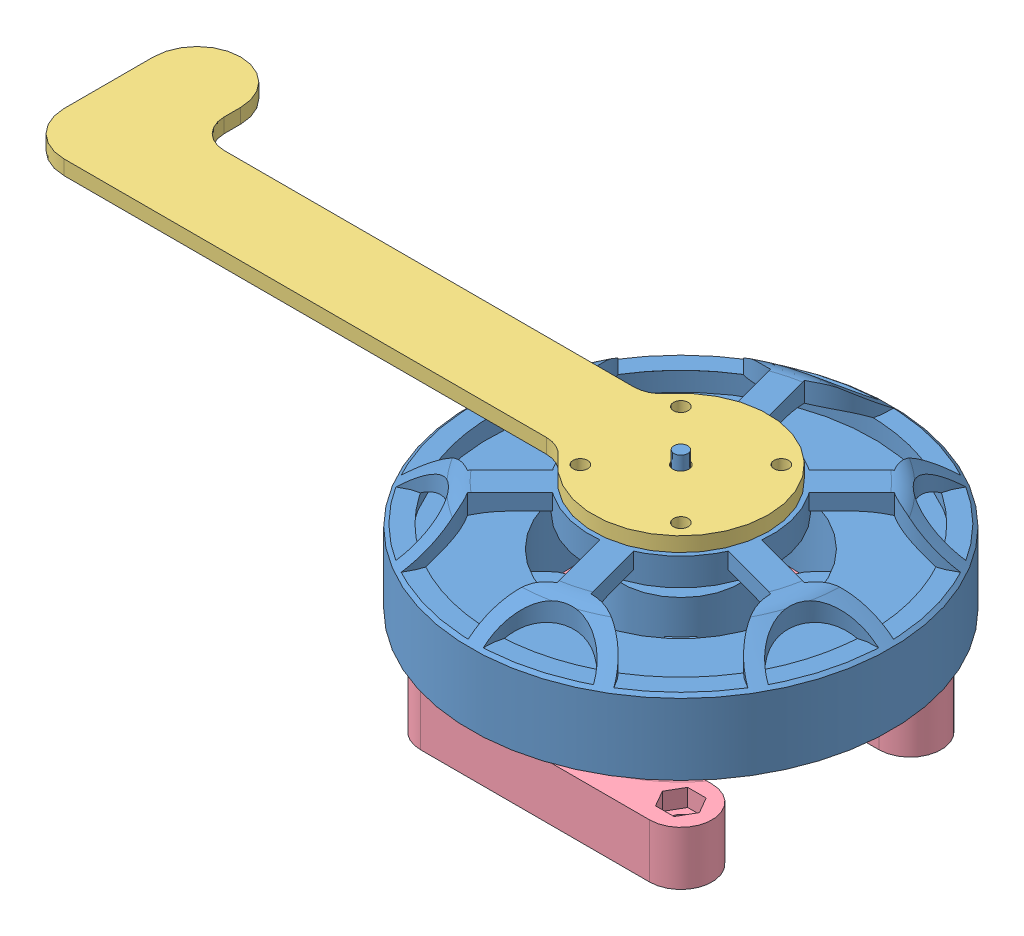
SolidWorks assembly Torque Tester Flat, configuration Default. Lengths in mm.
Overall size (199.34 53.3 129.63).
7 component instances, 7 part files, 10 mates.
Components (placement in the parent):
- 9225 160kv-1: 9225 160kv [Default] at (0 -3.93 0) x (0.707107 0 0.707107) z (-0.707107 0 0.707107) size (91.66 44.53 91.66)
- Magnut hex puck-1: Magnut hex puck [Default] at (0 -3.93 0) size (22.88 4.76 22.88)
- Part8^Torque Tester Flat-1: Part8^Torque Tester Flat [Default] at origin size (153.58 3.18 48.05) (virtual)
- MotorMountTorque Tester Flat-1: MotorMountTorque Tester Flat [Default] at origin size (63.59 19.05 63.59)
- encoder final board-1: encoder final board [Default] at (0 -9.105 0) size (25 4 25)
- Encoder Magnet-2: Encoder Magnet [Default] at (0 -5.5175 0) size (6.35 3.17 6.35)
- Part2^Torque Tester Flat-1: Part2^Torque Tester Flat [Default] at origin size (34.92 2.54 34.92) (virtual)
Mates (geometry in assembly coordinates):
- Coincident5: coincident: point of 9225 160kv-1; point of Magnut hex puck-1
- Coincident2: coincident aligned: line of 9225 160kv-1 through (41.998 0 36.159) axis (0 0 -1)
- Parallel4: parallel aligned: plane of 9225 160kv-1; plane of MotorMountTorque Tester Flat-1 through (-3.25 -3.175 -37.5487) normal (0 0 1)
- Coincident9: coincident anti-aligned: plane of 9225 160kv-1 through (6.8236 0 6.8236) normal (0 -1 0); plane of MotorMountTorque Tester Flat-1 through (0 0 0) normal (0 1 0)
- Parallel5: parallel aligned: plane of 9225 160kv-1 through (-3.25 -10.28 -36.33) normal (0 0 -1); plane of MotorMountTorque Tester Flat-1 through (0 -19.05 -31.7939) normal (0 0 -1)
- Coincident10: coincident anti-aligned: line of encoder final board-1 through (4.4 0 -10.305) axis (0 0 1)
- Coincident11: coincident aligned: plane of encoder final board-1 through (0 -9.105 0) normal (0 0 1)
- Coincident12: coincident: unknown of Encoder Magnet-2
- Coincident13: coincident anti-aligned: plane of 9225 160kv-1 through (0 -3.93 0) normal (0 -1 0); plane of Encoder Magnet-2 through (0 -3.93 0) normal (0 1 0)
- Distance1: distance = 1 mm anti-aligned: plane of encoder final board-1 through (0 -8.105 0) normal (0 1 0); plane of Encoder Magnet-2 through (0 -7.105 0) normal (0 -1 0)
